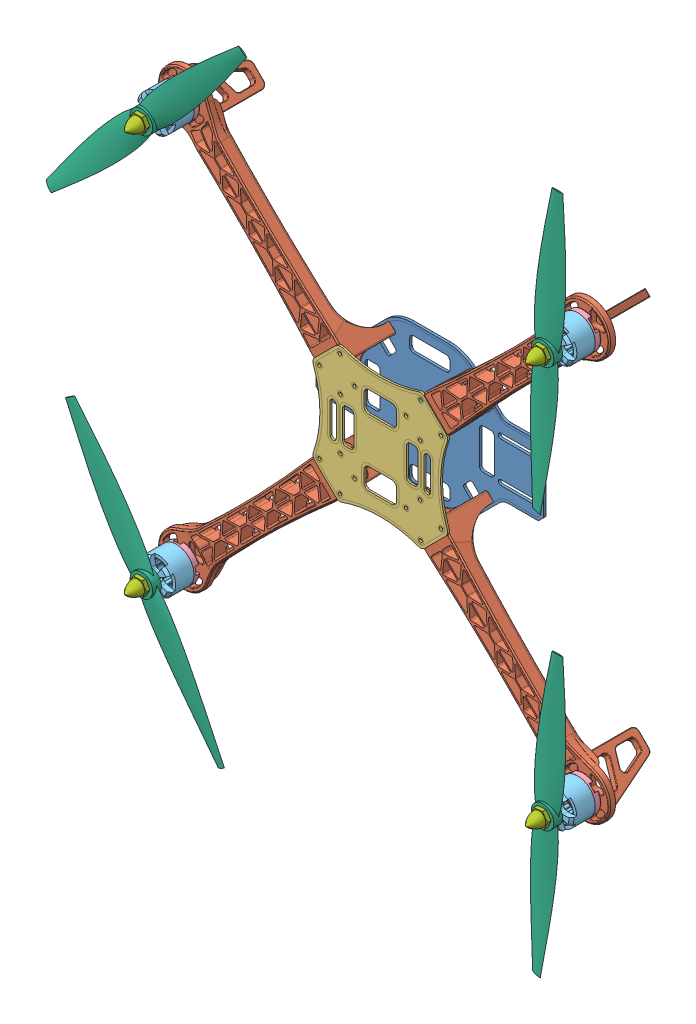
SolidWorks assembly Assem2, configuration Varsayılan. Lengths in mm.
Overall size (435.52 551.53 98.96).
26 component instances, 7 part files, 39 mates.
Components (placement in the parent):
- Part2-1: Part2 [Varsayılan] at (9.3113 16.2243 181) size (181 118 2)
- Part1-1: Part1 [Varsayılan] at (107.2464 -81.7109 216.5) x (0.707107 -0.707107 0) z (-0.707107 -0.707107 0) size (215.31 54.8 40.6)
- Part1-2: Part1 [Varsayılan] at (-88.6238 114.1594 216.5) x (-0.707107 0.707107 0) z (0.707107 0.707107 0) size (215.31 54.8 40.6)
- Part1-3: Part1 [Varsayılan] at (-88.6238 -81.7109 216.5) x (-0.707107 -0.707107 0) z (-0.707107 0.707107 0) size (215.31 54.8 40.6)
- Part1-4: Part1 [Varsayılan] at (107.2464 114.1594 216.5) x (0.707107 0.707107 0) z (0.707107 -0.707107 0) size (215.31 54.8 40.6)
- Part3-1: Part3 [Varsayılan] at (9.307 16.2269 221) size (107.26 107.26 1.5)
- Assem1-1: Assem1 [Varsayılan] at (149.0983 -123.9963 223.0153) x (0.715843 0.698261 0) z (0.698261 -0.715843 0) size (28 39.31 28)
  - Moteur brushless - Base-1: Moteur brushless - Base [Défaut] at (0.6547 -3.0153 28) size (28 5.06 28)
  - Part7-1: Part7 [Varsayılan] at (0.6547 1.9847 28) size (28 34.24 28)
- Assem1-2: Assem1 [Varsayılan] at (189.1198 195.6366 223.0153) x (0.683113 -0.730312 0) z (-0.730312 -0.683113 0) size (28 39.31 28)
  - Moteur brushless - Base-1: Moteur brushless - Base [Défaut] at (0.6547 -3.0153 28) size (28 5.06 28)
  - Part7-1: Part7 [Varsayılan] at (0.6547 1.9847 28) size (28 34.24 28)
- Assem1-3: Assem1 [Varsayılan] at (-170.3338 156.2606 223.0153) x (-0.689149 0.724619 0) z (0.724619 0.689149 0) size (28 39.31 28)
  - Moteur brushless - Base-1: Moteur brushless - Base [Défaut] at (0.6547 -3.0153 28) size (28 5.06 28)
  - Part7-1: Part7 [Varsayılan] at (0.6547 1.9847 28) size (28 34.24 28)
- Assem1-4: Assem1 [Varsayılan] at (-178.2548 -147.305 223.0153) x (-0.109698 0.993965 0) z (0.993965 0.109698 0) size (28 39.31 28)
  - Moteur brushless - Base-1: Moteur brushless - Base [Défaut] at (0.6547 -3.0153 28) size (28 5.06 28)
  - Part7-1: Part7 [Varsayılan] at (0.6547 1.9847 28) size (28 34.24 28)
- Part6-1: Part6 [Varsayılan] at (-149.687 175.2964 234.5398) x (0.738071 -0.67078 0.072843) z (-0.672566 -0.740037 0) size (24.84 8.29 230.68)
- Part6-2: Part6 [Varsayılan] at (-149.565 -143.0102 234.5398) x (0.849503 0.52253 0.072843) z (0.523922 -0.851766 0) size (24.84 8.29 230.68)
- Part6-3: Part6 [Varsayılan] at (170.208 -143.6622 234.5398) x (0.994694 -0.072649 0.072843) z (-0.072843 -0.997343 0) size (24.84 8.29 230.68)
- Part6-4: Part6 [Varsayılan] at (170.208 175.9517 234.5398) x (0.994694 -0.072649 0.072843) z (-0.072843 -0.997343 0) size (24.84 8.29 230.68)
- Part4-1: Part4 [Varsayılan] at (-161.5746 176.0312 241.1014) x (1 0 0) z (0 -1 0) size (13.86 13.5 12)
- Part4-2: Part4 [Varsayılan] at (158.0393 176.0312 241.1014) x (1 0 0) z (0 -1 0) size (13.86 13.5 12)
- Part4-4: Part4 [Varsayılan] at (164.5388 -153.6709 241.1014) x (0.41335 0.910572 0) z (0.910572 -0.41335 0) size (13.86 13.5 12)
- Part4-5: Part4 [Varsayılan] at (-161.5746 -143.5827 241.1014) x (1 0 0) z (0 -1 0) size (13.86 13.5 12)
Mates (geometry in assembly coordinates):
- Eş Merkezli2: concentric aligned: cylinder of Part2-1 through (39.9369 -29.2506 183) axis (0 0 -1) radius 1.35; cylinder of Part1-1 through (39.9369 -29.2506 188) axis (0 0 -1) radius 1.05
- Eş Merkezli3: concentric aligned: cylinder of Part2-1 through (54.7862 -14.4014 183) axis (0 0 -1) radius 1.25; cylinder of Part1-1 through (54.7862 -14.4014 188) axis (0 0 -1) radius 1.05
- Çakışık1: coincident anti-aligned: plane of Part2-1 through (71.9535 53.7243 183) normal (0 0 1); plane of Part1-1 through (36.1822 -29.0314 183) normal (0 0 -1)
- Eş Merkezli4: concentric aligned: cylinder of Part2-1 through (-21.3143 61.6991 183) axis (0 0 -1) radius 1.35; cylinder of Part1-2 through (-21.3143 61.6991 188) axis (0 0 -1) radius 1.05
- Eş Merkezli5: concentric aligned: cylinder of Part2-1 through (-36.1636 46.8499 183) axis (0 0 -1) radius 1.25; cylinder of Part1-2 through (-36.1636 46.8499 188) axis (0 0 -1) radius 1.05
- Çakışık2: coincident anti-aligned: plane of Part2-1 through (71.9535 53.7243 183) normal (0 0 1); plane of Part1-2 through (-17.5596 61.4799 183) normal (0 0 -1)
- Eş Merkezli8: concentric anti-aligned: circle of Part2-1; circle of Part1-4
- Eş Merkezli9: concentric aligned: cylinder of Part2-1 through (39.9369 61.6991 183) axis (0 0 -1) radius 1.35; cylinder of Part1-4 through (39.9369 61.6991 188) axis (0 0 -1) radius 1.05
- Çakışık3: coincident anti-aligned: plane of Part2-1 through (71.9535 53.7243 183) normal (0 0 1); plane of Part1-4 through (54.567 43.0952 183) normal (0 0 -1)
- Eş Merkezli10: concentric aligned: cylinder of Part2-1 through (-21.3143 -29.2506 183) axis (0 0 -1) radius 1.35; cylinder of Part1-3 through (-21.3143 -29.2506 188) axis (0 0 -1) radius 1.05
- Eş Merkezli11: concentric anti-aligned: circle of Part2-1; cylinder of Part1-3 through (-36.1636 -14.4014 188) axis (0 0 -1) radius 1.05
- Çakışık4: coincident anti-aligned: plane of Part2-1 through (71.9535 53.7243 183) normal (0 0 1); plane of Part1-3 through (-35.9444 -10.6466 183) normal (0 0 -1)
- Eş Merkezli12: concentric aligned: cylinder of Part1-3 through (-22.8664 -32.2099 212.7473) axis (0 0 1) radius 1.15; circle of Part3-1
- Çakışık5: coincident anti-aligned: plane of Part1-4 through (107.2464 114.1594 221) normal (0 0 1); plane of Part3-1 through (9.307 -121.8594 221) normal (0 0 -1)
- Eş Merkezli26: concentric aligned: cylinder of Part1-1 through (169.1183 -143.5827 211) axis (0 0 1) radius 5; cylinder of Assem1-1/Moteur brushless - Base-1 through (169.1183 -143.5827 220) axis (0 0 1) radius 4
- Çakışık7: coincident anti-aligned: plane of Part1-1 through (169.1183 -143.5827 220) normal (0 0 1); plane of Assem1-1/Moteur brushless - Base-1 through (169.1183 -143.5827 220) normal (0 0 -1)
- Eş Merkezli30: concentric aligned: circle of Part1-3; cylinder of Assem1-4/Moteur brushless - Base-1 through (-150.4957 -143.5827 220) axis (0 0 1) radius 4
- Çakışık8: coincident anti-aligned: plane of Part1-3 through (-150.4957 -143.5827 220) normal (0 0 1); plane of Assem1-4/Moteur brushless - Base-1 through (-150.4957 -143.5827 220) normal (0 0 -1)
- Eş Merkezli31: concentric aligned: circle of Part1-3; circle of Assem1-4/Moteur brushless - Base-1
- Eş Merkezli32: concentric aligned: cylinder of Part1-2 through (-150.4957 176.0312 211) axis (0 0 1) radius 5; cylinder of Assem1-3/Moteur brushless - Base-1 through (-150.4957 176.0312 220) axis (0 0 1) radius 4
- Çakışık9: coincident anti-aligned: plane of Part1-2 through (-150.4957 176.0312 220) normal (0 0 1); plane of Assem1-3/Moteur brushless - Base-1 through (-150.4957 176.0312 220) normal (0 0 -1)
- Eş Merkezli33: concentric aligned: cylinder of Part1-4 through (169.1183 176.0312 211) axis (0 0 1) radius 5; cylinder of Assem1-2/Moteur brushless - Base-1 through (169.1183 176.0312 220) axis (0 0 1) radius 4
- Çakışık10: coincident anti-aligned: plane of Part1-4 through (169.1183 176.0312 220) normal (0 0 1); plane of Assem1-2/Moteur brushless - Base-1 through (169.1183 176.0312 220) normal (0 0 -1)
- Eş Merkezli34: concentric anti-aligned: cylinder of Assem1-3/Part7-1 through (-150.4957 176.0312 259) axis (0 0 1) radius 3.25; cylinder of Part6-1 through (-150.4957 176.0312 261) axis (0 0 -1) radius 3.25
- Çakışık11: coincident aligned: circle of Assem1-3/Part7-1; plane of Part6-1 through (-149.687 175.2964 246) normal (0 0 -1)
- Çakışık12: coincident anti-aligned: cylinder of Assem1-4/Part7-1 through (-150.4957 -143.5827 259) axis (0 0 1) radius 3.25; circle of Part6-2
- Çakışık13: coincident anti-aligned: plane of Assem1-4/Part7-1 through (-151.812 -131.6551 246) normal (0 0 1); plane of Part6-2 through (-149.565 -143.0102 246) normal (0 0 -1)
- Eş Merkezli35: concentric anti-aligned: cylinder of Assem1-1/Part7-1 through (169.1183 -143.5827 259) axis (0 0 1) radius 3.25; cylinder of Part6-3 through (169.1183 -143.5827 261) axis (0 0 -1) radius 3.25
- Çakışık14: coincident anti-aligned: plane of Assem1-1/Part7-1 through (177.7084 -135.2036 246) normal (0 0 1); plane of Part6-3 through (170.208 -143.6622 246) normal (0 0 -1)
- Eş Merkezli37: concentric anti-aligned: cylinder of Assem1-2/Part7-1 through (169.1183 176.0312 259) axis (0 0 1) radius 3.25; cylinder of Part6-4 through (169.1183 176.0312 261) axis (0 0 -1) radius 3.25
- Çakışık15: coincident anti-aligned: plane of Assem1-2/Part7-1 through (177.3156 167.2675 246) normal (0 0 1); plane of Part6-4 through (170.208 175.9517 246) normal (0 0 -1)
- Eş Merkezli38: concentric anti-aligned: cylinder of Assem1-1/Part7-1 through (169.1183 -143.5827 259) axis (0 0 1) radius 2.25; cylinder of Part4-4 through (169.1183 -143.5827 263.5) axis (0 0 -1) radius 2.5
- Çakışık16: coincident anti-aligned: plane of Part6-3 through (170.208 -143.6622 253) normal (0 0 1); plane of Part4-4 through (164.5388 -153.6709 253) normal (0 0 -1)
- Eş Merkezli39: concentric anti-aligned: cylinder of Assem1-2/Part7-1 through (169.1183 176.0312 259) axis (0 0 1) radius 2.25; cylinder of Part4-2 through (169.1183 176.0312 263.5) axis (0 0 -1) radius 2.5
- Çakışık17: coincident anti-aligned: plane of Part6-4 through (170.208 175.9517 253) normal (0 0 1); plane of Part4-2 through (158.0393 176.0312 253) normal (0 0 -1)
- Eş Merkezli40: concentric anti-aligned: cylinder of Assem1-4/Part7-1 through (-150.4957 -143.5827 259) axis (0 0 1) radius 2.25; cylinder of Part4-5 through (-150.4957 -143.5827 263.5) axis (0 0 -1) radius 2.5
- Çakışık18: coincident anti-aligned: plane of Part6-2 through (-149.565 -143.0102 253) normal (0 0 1); plane of Part4-5 through (-161.5746 -143.5827 253) normal (0 0 -1)
- Eş Merkezli41: concentric anti-aligned: cylinder of Assem1-3/Part7-1 through (-150.4957 176.0312 259) axis (0 0 1) radius 2.25; circle of Part4-1
- Çakışık19: coincident anti-aligned: plane of Part6-1 through (-149.687 175.2964 253) normal (0 0 1); plane of Part4-1 through (-161.5746 176.0312 253) normal (0 0 -1)
